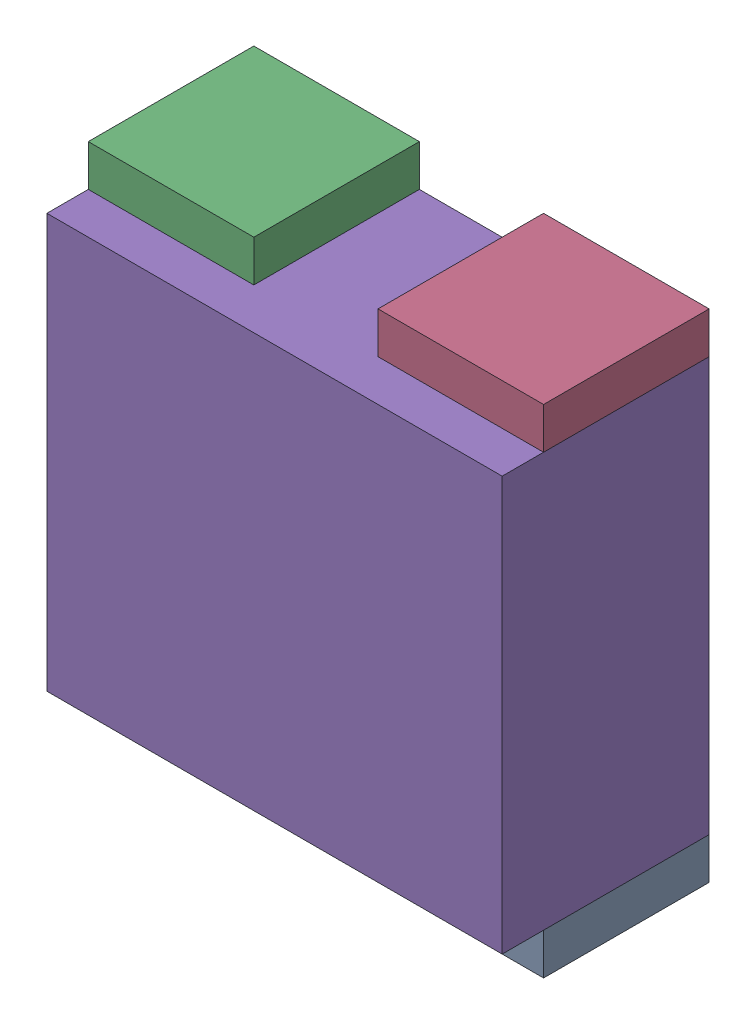
SolidWorks assembly RN13, configuration Default. Lengths in mm.
Overall size (1.1 1.2 0.5).
10 component instances, 2 part files, 0 mates.
Components (placement in the parent):
- 810157616-1: 810157616 [Default] at (125.8 59.95 0) size (0.4 0.1 0.4)
  - Extruded_12-1: Extruded_12 [Default] at origin size (0.4 0.1 0.4)
- 810157616-2: 810157616 [Default] at (125.1 59.95 0) size (0.4 0.1 0.4)
  - Extruded_12-1: Extruded_12 [Default] at origin size (0.4 0.1 0.4)
- 810157616-3: 810157616 [Default] at (125.1 61.05 0) size (0.4 0.1 0.4)
  - Extruded_12-1: Extruded_12 [Default] at origin size (0.4 0.1 0.4)
- 810157616-4: 810157616 [Default] at (125.8 61.05 0) size (0.4 0.1 0.4)
  - Extruded_12-1: Extruded_12 [Default] at origin size (0.4 0.1 0.4)
- 810156720-1: 810156720 [Default] at (125.45 60.5 0) size (1.1 1 0.5)
  - Extruded_13-1: Extruded_13 [Default] at origin size (1.1 1 0.5)
